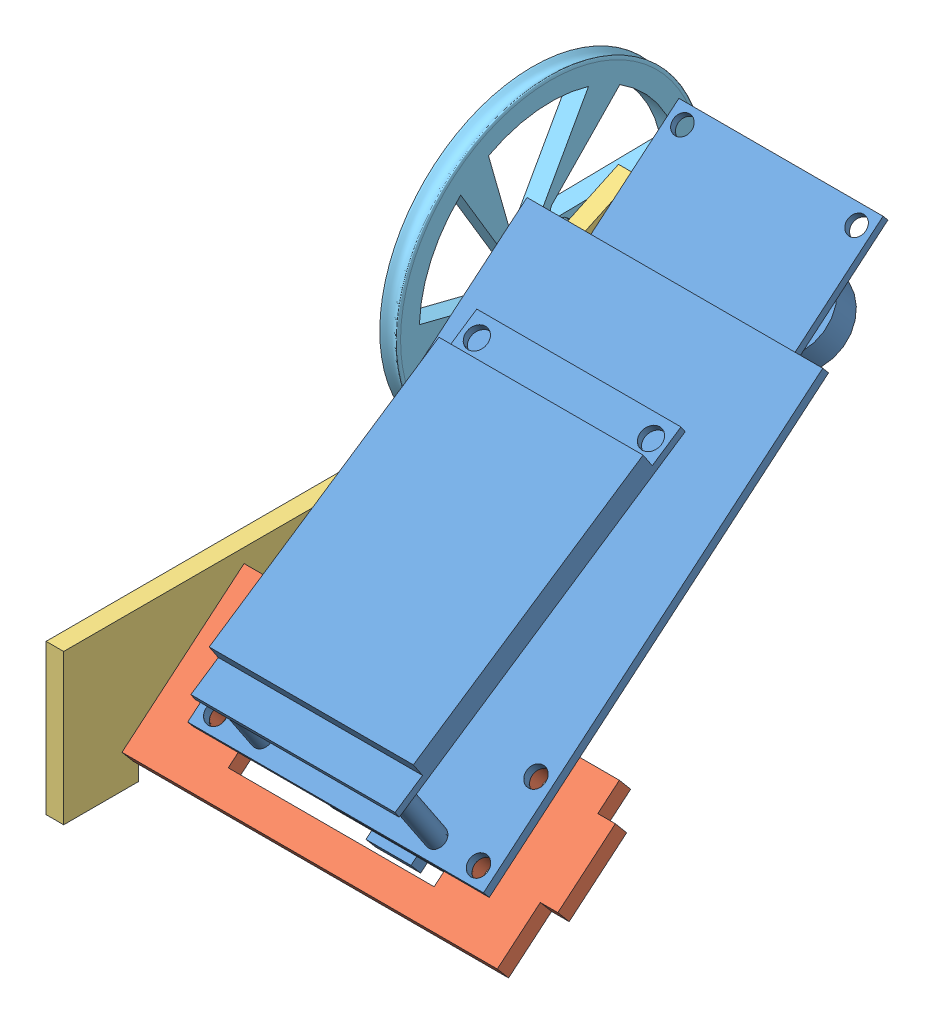
SolidWorks assembly Assembly, configuration Default. Lengths in mm.
Overall size (80.82 93.26 129.76).
5 component instances, 5 part files, 13 mates.
Components (placement in the parent):
- Camera Board-1: Camera Board [Default] at (44.6744 34.2509 106.2404) x (1 0 0) z (0 -0.642788 0.766044) size (50.04 42.04 95)
- Board Mount-1: Board Mount [Default] at (44.6292 13.615 126.21) x (1 0 0) z (0 -0.642788 0.766044) size (69.44 2.97 26.96)
- Side Wall-1: Side Wall [Default] at (12.8792 0 150.1343) x (0 0 1) z (-1 0 0) size (107.57 46.87 2.97)
- TT Motor-1: TT Motor [Default] at (33.1992 20.599 79.5794) x (0 0.422618 -0.906308) z (-1 0 0) size (67.56 20.32 29.46)
- Wheel 2in-1: Wheel 2in [Default] at (1.7032 31.3335 56.5592) x (-1 0 0) z (0 -0.87364 0.486572) size (15.88 53.2 53.2)
Mates (geometry in assembly coordinates):
- Concentric1: concentric aligned: cylinder of Camera Board-1 through (22.4494 21.1324 124.2453) axis (0 -0.766044 -0.642788) radius 1.651; cylinder of Board Mount-1 through (22.4494 19.9649 123.2657) axis (0 -0.766044 -0.642788) radius 1.6476
- Parallel1: parallel aligned: cylinder of Camera Board-1 through (66.8994 21.1324 124.2453) axis (0 -0.766044 -0.642788) radius 1.651; cylinder of Board Mount-1 through (66.809 19.9649 123.2657) axis (0 -0.766044 -0.642788) radius 1.6476
- Coincident1: coincident anti-aligned: plane of Camera Board-1 through (44.6744 34.2509 106.2404) normal (0 -0.766044 -0.642788); plane of Board Mount-1 through (44.6292 15.8915 128.1202) normal (0 0.766044 0.642788)
- Coincident2: coincident anti-aligned: plane of Board Mount-1 through (44.6292 11.8015 132.9945) normal (0 -0.642788 0.766044); plane of Side Wall-1 through (9.9074 13.3158 134.2651) normal (0 0.642788 -0.766044)
- Coincident3: coincident anti-aligned: plane of Board Mount-1 through (44.6292 13.615 126.21) normal (0 -0.766044 -0.642788); plane of Side Wall-1 through (9.9074 -3.7908 146.9534) normal (0 0.766044 0.642788)
- Coincident4: coincident anti-aligned: plane of Board Mount-1 through (12.8792 15.8915 128.1202) normal (-1 0 0); plane of Side Wall-1 through (12.8792 0 150.1343) normal (1 0 0)
- Concentric3: concentric anti-aligned: cylinder of Side Wall-1 through (9.9074 30.0393 77.8158) axis (1 0 0) radius 2.159; cylinder of TT Motor-1 through (33.1992 30.0393 77.8158) axis (-1 0 0) radius 1.5875
- Concentric4: concentric anti-aligned: cylinder of Side Wall-1 through (9.9074 15.8818 71.2141) axis (1 0 0) radius 2.159; cylinder of TT Motor-1 through (33.1992 15.8818 71.2141) axis (-1 0 0) radius 1.5875
- Coincident5: coincident anti-aligned: plane of Side Wall-1 through (12.8792 0 150.1343) normal (1 0 0); circle of TT Motor-1
- Concentric5: concentric anti-aligned: cylinder of TT Motor-1 through (6.0212 31.3335 56.5592) axis (1 0 0) radius 2.54; cylinder of Wheel 2in-1 through (14.4032 31.3335 56.5592) axis (-1 0 0) radius 4.7625
- Coincident6: coincident anti-aligned: plane of TT Motor-1 through (6.0212 31.2169 54.0218) normal (0 0.681261 -0.732041); plane of Wheel 2in-1 through (14.4032 31.2169 54.0218) normal (0 -0.681261 0.732041)
- Coincident7: coincident anti-aligned: plane of TT Motor-1 through (14.4032 20.599 79.5794) normal (-1 0 0); plane of Wheel 2in-1 through (14.4032 31.3335 56.5592) normal (1 0 0)
- Coincident8: coincident anti-aligned: plane of Side Wall-1 through (9.9074 0 150.1343) normal (0 -1 0)
